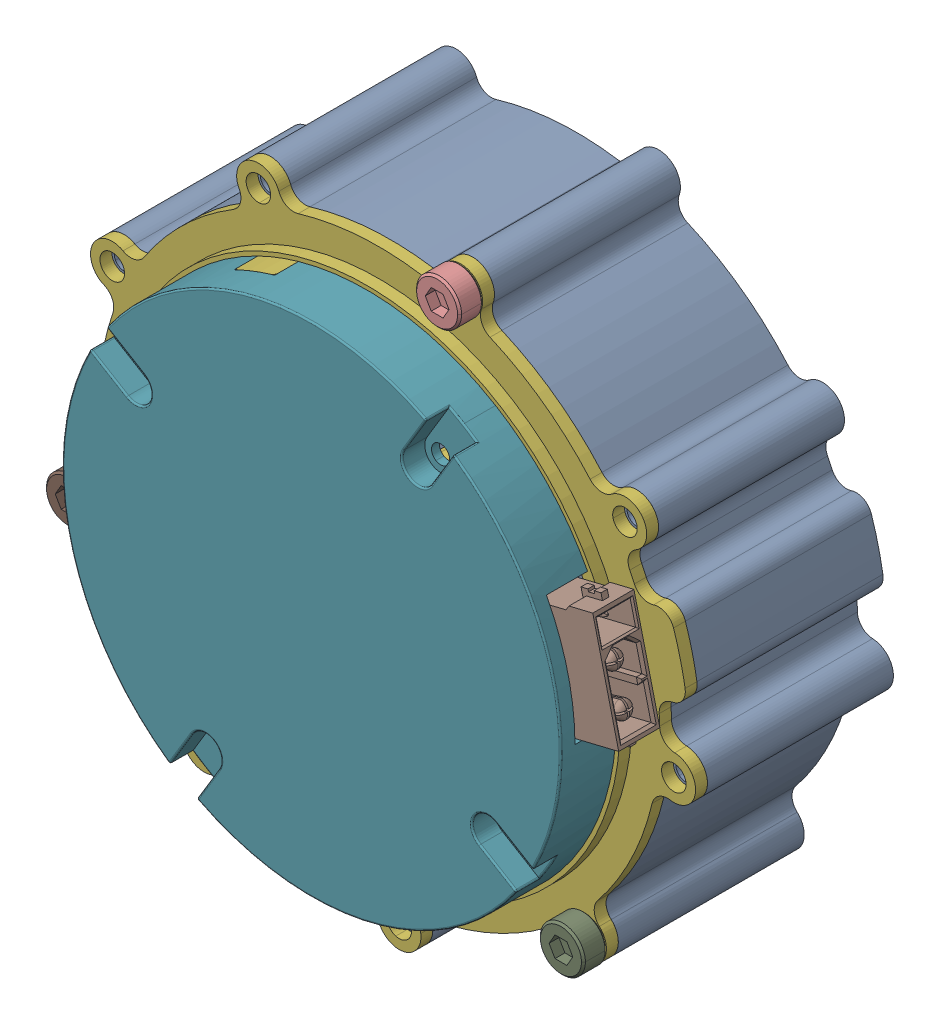
SolidWorks assembly ASM0002_ASM_1_ASM.stp, configuration 默认. Lengths in mm.
Overall size (96.28 96.17 36.5).
17 component instances, 9 part files, 0 mates.
Components (placement in the parent):
- ASM0002_ASM_1_ASM_1_ASM.stp-1: ASM0002_ASM_1_ASM_1_ASM.stp [默认] at origin size (96.28 96.17 36.5)
  - 0714_ASM_1_ASM_1_ASM_1_ASM.stp-1: 0714_ASM_1_ASM_1_ASM_1_ASM.stp [默认] at origin size (96.28 96.17 36.5)
    - 3_1_02_067_0003_ASM_ASM_1_ASM_1_ASM.stp-1: 3_1_02_067_0003_ASM_ASM_1_ASM_1_ASM.stp [默认] at origin size (96.28 96.17 36.5)
      - 3_1_02_067_0003_ASM_1_ASM_1_ASM_ASM.stp-1: 3_1_02_067_0003_ASM_1_ASM_1_ASM_ASM.stp [默认] at origin size (96.28 96.17 36.5)
        - 1_1_06_EB673-504_1_1_1_1_1.stp-1: 1_1_06_EB673-504_1_1_1_1_1.stp [默认] at (39.8324 39.833 -22) size (79.19 78.95 25.5)
        - 1_2_04_670601_1_1_1_1_1.stp-1: 1_2_04_670601_1_1_1_1_1.stp [默认] at (93.9161 79.9966 -44) size (37 37 4)
        - 1_1_02_EB671-500_1_1_1_1_1.stp-1: 1_1_02_EB671-500_1_1_1_1_1.stp [默认] at (93.9161 79.9966 -44.4) x (-0.960973 0.276644 0) z (0 0 1) size (33 33 8.5)
        - 1_2_04_694000_1_1_1_1_1.stp-1: 1_2_04_694000_1_1_1_1_1.stp [默认] at (93.9161 79.9966 -44.5) size (11 11 4)
        - 1_2_06_000213_1_1_1_1_1.stp-1: 1_2_06_000213_1_1_1_1_1.stp [默认] at (93.9161 79.9966 -45.5) size (38.8 36.2 1.5)
        - 1_1_31_QT-642_1_1_1_1_1.stp-1: 1_1_31_QT-642_1_1_1_1_1.stp [默认] at (93.9161 79.9966 -22) x (-0.970555 -0.24088 0) z (0 0 -1) size (79.5 79.36 6)
        - 1_1_06_EB673-502_1_1_1_1_1.stp-1: 1_1_06_EB673-502_1_1_1_1_1.stp [默认] at (93.9161 79.9966 -13) x (-0.515958 -0.856614 0) z (0 0 -1) size (63 63 8)
      - 0518_ASM_2_ASM_1_ASM_1_ASM_1_AS_ASM.stp-1: 0518_ASM_2_ASM_1_ASM_1_ASM_1_AS_ASM.stp [默认] at (93.9161 79.9966 -17.235) x (0.235897 -0.971778 0) z (0 0 1) size (15.5 11.3 5.2)
        - 12345_ASM_1_ASM_2_ASM_1_ASM_1_A_ASM.stp-1: 12345_ASM_1_ASM_2_ASM_1_ASM_1_A_ASM.stp [默认] at origin size (15.5 11.3 5.2)
          - DUANZI_1_3_1_1_1_1_1_1.stp-1: DUANZI_1_3_1_1_1_1_1_1.stp [默认] at (-0.1798 16.5474 0.4329) x (0 0 -1) z (0 1 0) size (5.2 15.5 11.3)
  - LUODING_1_1.stp-1: LUODING_1_1.stp [默认] at (119.9375 52.9941 -20.5) x (-1 0 0) z (0 1 0) size (5.68 3 5.68)
  - LUODING_1_1.stp-2: LUODING_1_1.stp [默认] at (104.2902 116.0331 -20.5) x (-1 0 0) z (0 1 0) size (5.68 3 5.68)
  - LUODING_1_1.stp-3: LUODING_1_1.stp [默认] at (57.5205 70.9626 -20.5) x (-1 0 0) z (0 1 0) size (5.68 3 5.68)
